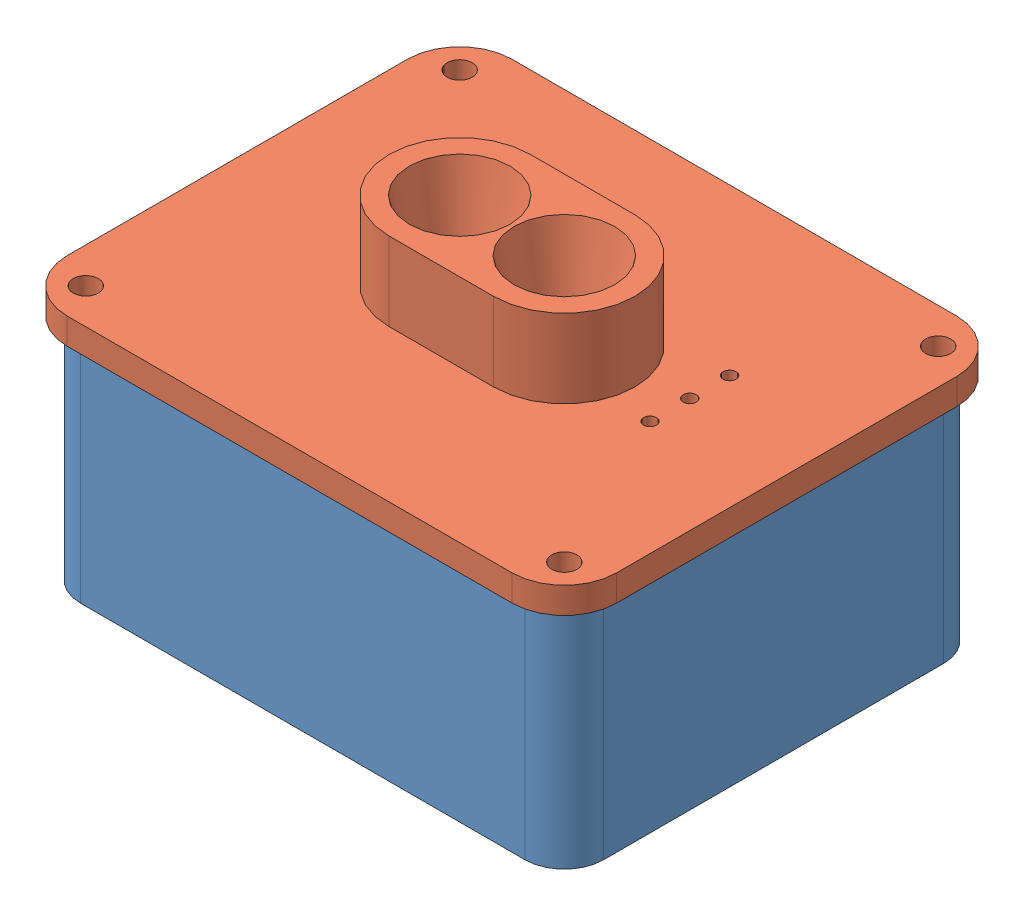
SolidWorks assembly Enclosure_NoSolarPanel, configuration Default. Lengths in mm.
Overall size (133.35 80.96 107.95).
2 component instances, 2 part files, 2 mates.
Components (placement in the parent):
- TelemetryEnclosurer-NoSolar-1: TelemetryEnclosurer-NoSolar [Default] at (34.3299 35.9255 106.1285) size (127 55.56 101.6)
- TelemetryEnclosure-NoSolar_Lid_UltraSonicSensor-1: TelemetryEnclosure-NoSolar_Lid_UltraSonicSensor [Default] at origin size (133.35 25.4 107.95)
Mates (geometry in assembly coordinates):
- Parallel1: parallel: plane of assembly through (0 0 0) normal (0 1 0); plane of TelemetryEnclosurer-NoSolar-1 through (-19.6451 35.9255 147.4035) normal (0 -1 0); plane of assembly
- Parallel2: parallel: plane of assembly through (0 0 0) normal (1 0 0); plane of TelemetryEnclosurer-NoSolar-1 through (97.8299 40.688 64.8535) normal (1 0 0); plane of assembly
